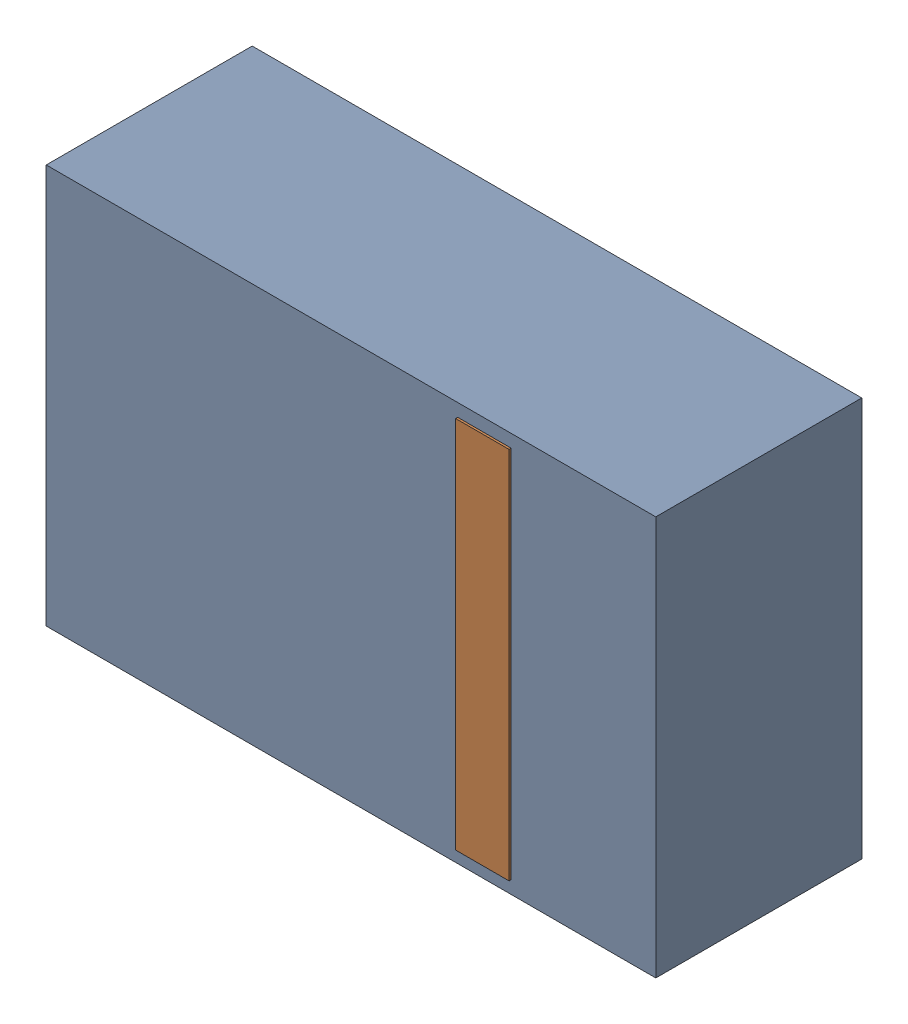
SolidWorks assembly D11, configuration Default. Lengths in mm.
Overall size (2.9 1.9 0.99).
4 component instances, 2 part files, 0 mates.
Components (placement in the parent):
- 905269392-1: 905269392 [Default] at (109.474 72.898 0) size (2.9 1.9 0.98)
  - Extruded_5-1: Extruded_5 [Default] at origin size (2.9 1.9 0.98)
- 905269800-1: 905269800 [Default] at (110.109 72.898 0.95) size (0.25 1.78 0.04)
  - Extruded_6-1: Extruded_6 [Default] at origin size (0.25 1.78 0.04)
